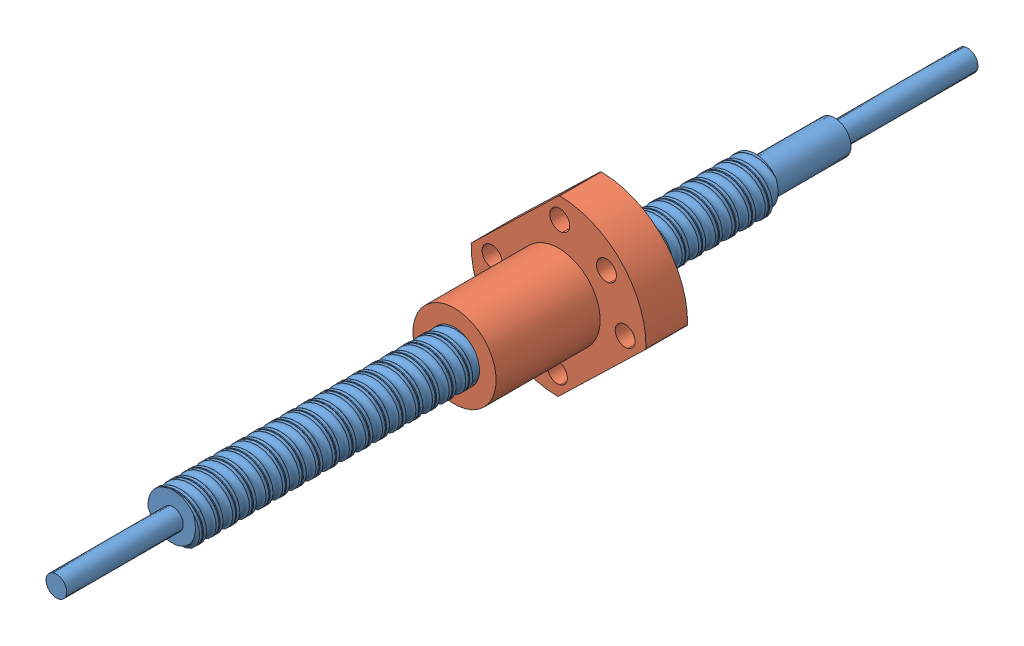
SolidWorks assembly Z-axis screw assembly, configuration Default. Lengths in mm.
Overall size (51.05 50.76 219).
2 component instances, 2 part files, 2 mates.
Components (placement in the parent):
- Z-axis ball screw-4: Z-axis ball screw [Default] at (19.7367 -90.9896 -238.1146) x (0.899681 -0.436549 0) z (0 0 1) size (12.18 12.18 219)
- Z-axis ball screw nut-5: Z-axis ball screw nut [Default] at (19.7367 -90.9896 -200.8096) x (0.694849 -0.719155 0) z (0 0 1) size (30 42 35)
Mates (geometry in assembly coordinates):
- Concentric7: concentric anti-aligned: cylinder of Z-axis ball screw-4 through (19.7367 -90.9896 -257.1146) axis (0 0 1) radius 4; cylinder of Z-axis ball screw nut-5 through (19.7367 -90.9896 -165.8096) axis (0 0 -1) radius 10
- Screw5: screw = 1 mm anti-aligned: cylinder of Z-axis ball screw-4 through (19.7367 -90.9896 -257.1146) axis (0 0 1) radius 4; cylinder of Z-axis ball screw nut-5 through (19.7367 -90.9896 -165.8096) axis (0 0 -1) radius 10
